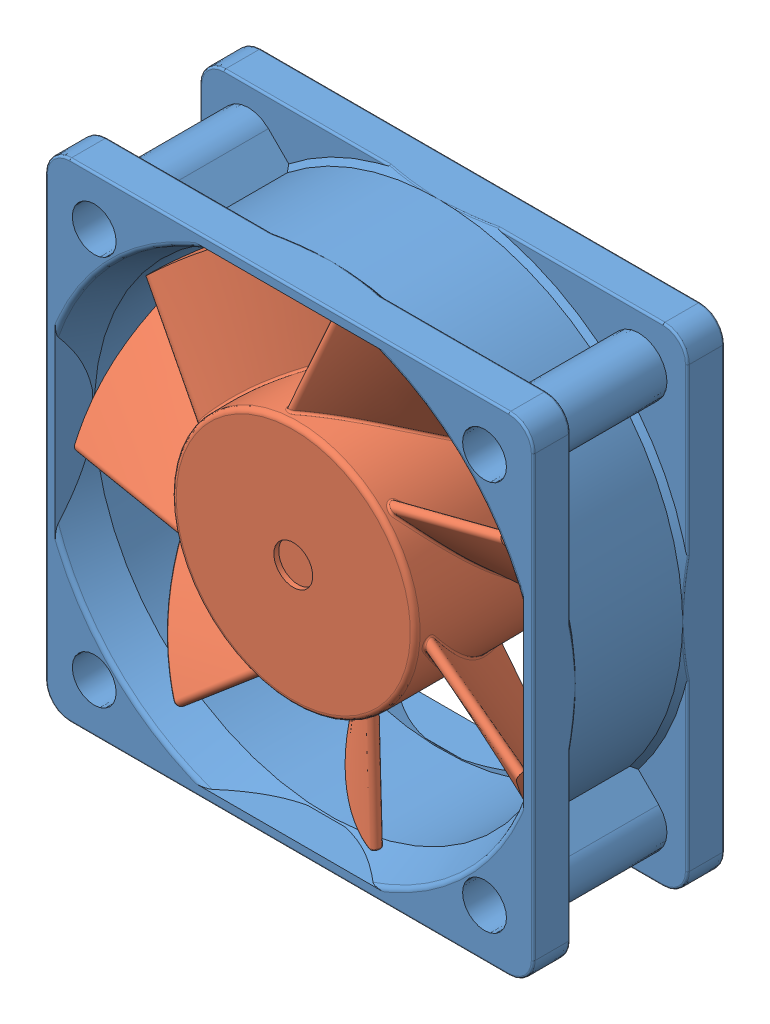
SolidWorks assembly PC fan 50x20mm, configuration По умолчанию. Lengths in mm.
Overall size (53.34 53.7 20.67).
2 component instances, 2 part files, 2 mates.
Components (placement in the parent):
- PC fan 50x20mm body-1: PC fan 50x20mm body [По умолчанию] at origin size (50 50 20.39)
- PC fan 50x20mm prop-1: PC fan 50x20mm prop [По умолчанию] at (0 0 7.9) x (-0.992876 -0.11915 0) z (0 0 1) size (47.92 48.34 17.96)
Mates (geometry in assembly coordinates):
- Концентричный1: concentric: cylinder of PC fan 50x20mm body-1 through (0 0 -9.8) axis (0 0 -1) radius 24; cylinder of PC fan 50x20mm prop-1 through (0 0 9.4) axis (0 0 -1) radius 12.5
- Расстояние1: distance = 1 mm: plane of PC fan 50x20mm prop-1 through (0 0 -5.6) normal (0 0 -1); plane of PC fan 50x20mm body-1 through (0 0 -6.6) normal (0 0 1)
